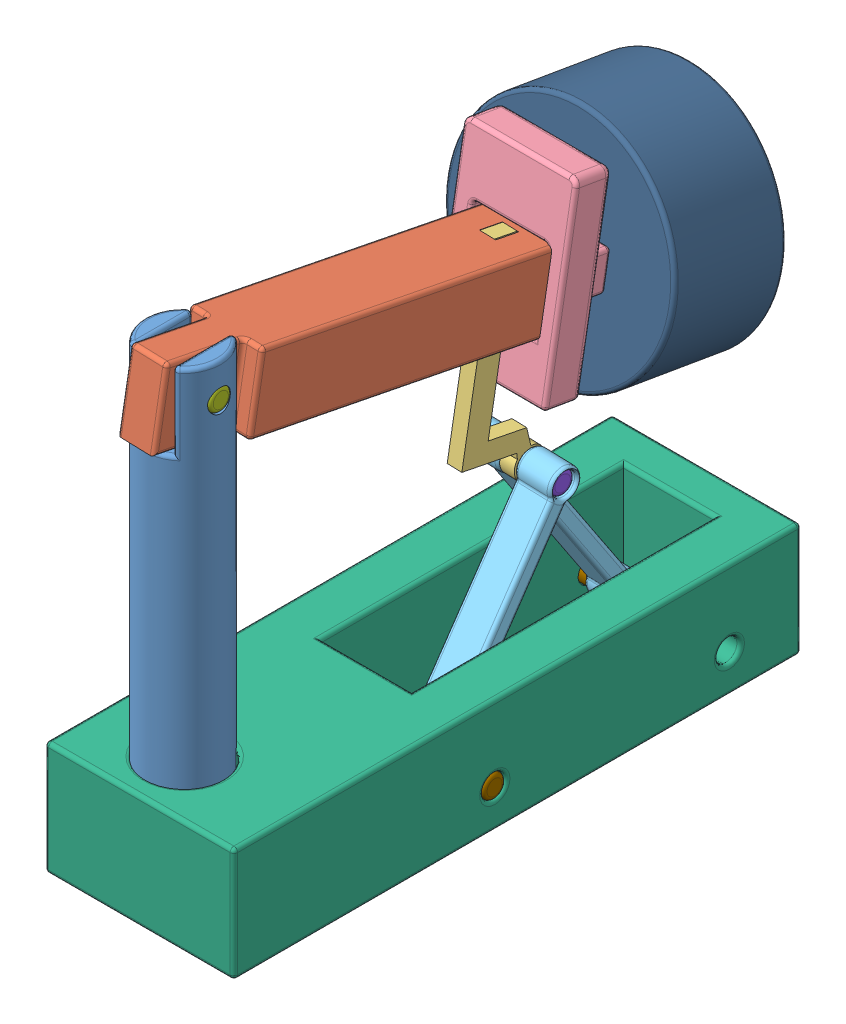
SolidWorks assembly Nomad Drive Train, configuration Default. Lengths in mm.
Overall size (695.42 1346.04 1500).
13 component instances, 11 part files, 9 mates.
Components (placement in the parent):
- Part1-2: Part1 [Default] at (310.573 -42.1578 1040.0417) size (200 1200 200)
- Part2-3: Part2 [Default] at (329.7558 1087.6226 640.8238) x (-0.032531 0.168435 0.985176) z (0.999465 0.002066 0.03265) size (1000 200 200)
- Part3-3: Part3 [Default] at (320.9887 772.0927 278.3109) x (-0.003464 -0.985711 0.168412) z (-0.032531 0.168435 0.985176) size (573.2 40 222.3)
- Part4-2: Part4 [Default] at (181.8507 917.6325 162.7293) x (-0.000294 -0.168412 -0.985717) z (-0.003464 -0.985711 0.168412) size (150 300 500)
- Part5,6-1: Part5,6 [Default] at (326.0278 276.1862 -130.2146)
- Part5,6(II)-1: Part5,6(II) [Default] at (225.0158 467.0752 175.3337) x (0.019664 -0.835542 -0.549074) z (-0.026146 -0.549422 0.835136) size (645.9 104.77 80)
- Part5,6(II)-4: Part5,6(II) [Default] at (464.8874 467.571 180.5308) x (-0.016125 -0.837244 0.546592) z (0.028465 -0.546826 -0.836763) size (645.9 104.77 80)
- Part7-1: Part7 [Default] at (339.2924 196.9457 434.0735) x (0 0 1) z (1 0 0) size (1500 300 500)
- Part10-1: Part10 [Default] at (411.7953 1067.7529 1040.9998) x (0 0 -1) z (0 1 0) size (60 200 60)
- Part11-1: Part11 [Default] at (454.887 467.8694 180.3609) x (-0.002075 0.999998 0.000254) z (-0.032649 -0.000322 0.999467) size (60 240 60)
- Part12-1: Part12 [Default] at (339.2924 -0.9652 -127.9931) x (0 1 0) z (0 0 1) size (60 250 60)
- Part12-3: Part12 [Default] at (589.2924 -3.604 494.7661) x (0 1 0) z (0 0 1) size (60 250 60)
- Tyre-1: Tyre [Default] at (330.0972 900.2777 64.2012) x (0.984716 -0.171728 0.029047) z (0.174167 0.970643 -0.165888) size (600 300.01 600)
Mates (geometry in assembly coordinates):
- Concentric1: concentric: circle of Part1-2; circle of Part2-3
- Coincident5: coincident anti-aligned: plane of Part2-3 through (365.6058 816.4141 241.7552) normal (-0.032531 0.168435 0.985176); plane of Part3-3 through (361.2504 569.9802 283.744) normal (0.032531 -0.168435 -0.985176)
- Coincident6: coincident: line of Part2-3 through (366.2986 1013.5572 208.0726) axis (-0.999465 -0.002066 -0.03265); plane of Part3-3 through (362.8092 1013.55 207.9586) normal (0.003464 0.985711 -0.168412)
- Coincident13: coincident anti-aligned: plane of Part2-3 through (329.7558 1087.6226 640.8238) normal (0.003464 0.985711 -0.168412); plane of Part4-2 through (232.139 995.3441 98.7126) normal (-0.003464 -0.985711 0.168412)
- Coincident14: coincident: circle of Part3-3; circle of Part5,6(II)-1
- Concentric11: concentric anti-aligned: cylinder of Part3-3 through (364.9409 467.3644 177.2659) axis (-0.999465 -0.002066 -0.03265) radius 40; cylinder of Part5,6(II)-4 through (364.9409 467.3644 177.2659) axis (0.999465 0.002066 0.03265) radius 40
- Coincident28: coincident anti-aligned: plane of Part3-3 through (364.9409 467.3644 177.2659) normal (0.999465 0.002066 0.03265); plane of Part5,6(II)-4 through (364.9409 467.3644 177.2659) normal (-0.999465 -0.002066 -0.03265)
- Coincident29: coincident aligned: circle of Part5,6(II)-4; plane of Part11-1 through (454.887 467.8694 180.3609) normal (0.999465 0.002066 0.03265)
- Coincident30: coincident anti-aligned: circle of Part4-2; circle of Tyre-1
